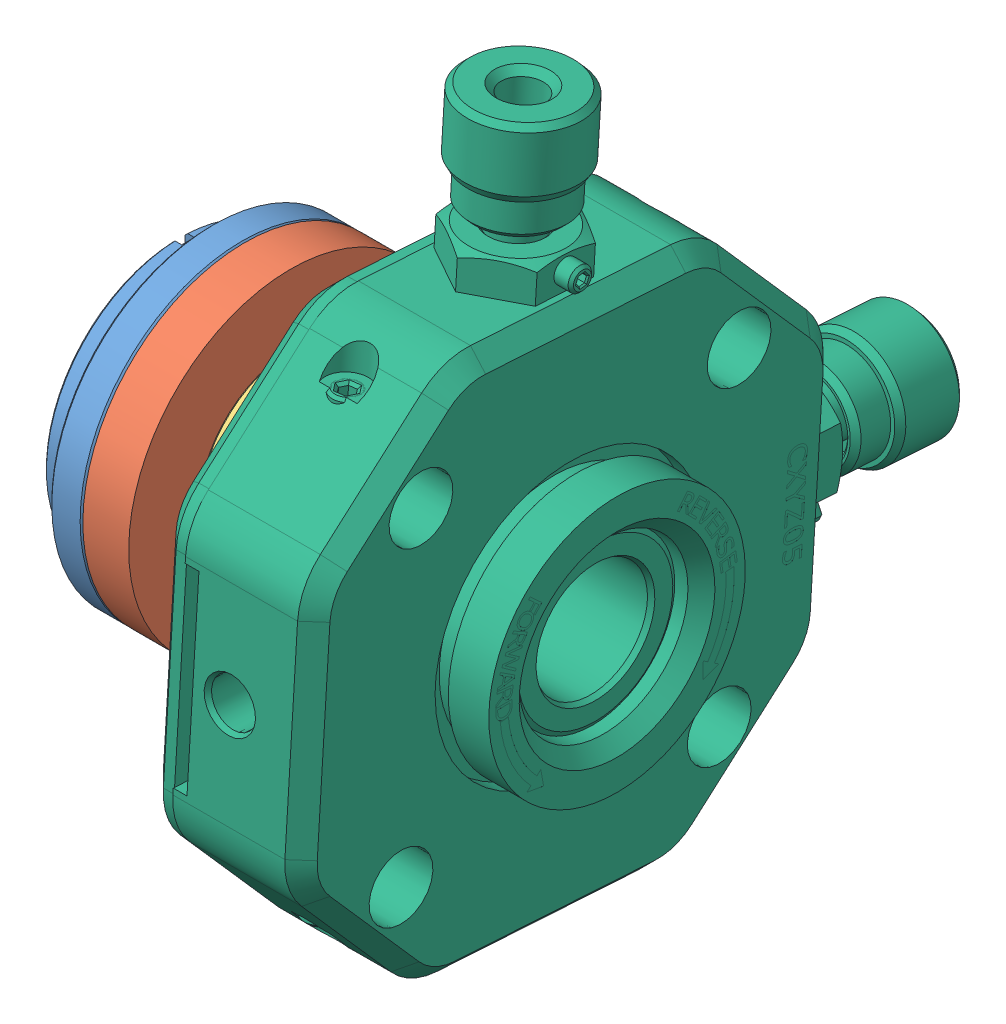
SolidWorks assembly Small Calibration Assembly S05, configuration Default. Lengths in mm.
Overall size (41.25 67.52 67.52).
6 component instances, 6 part files, 10 mates.
Components (placement in the parent):
- SM1A39-Solidworks-1: SM1A39-Solidworks [Default] at (11.2351 18.1088 21.9746) size (9.27 30.48 30.48)
- SM1A1-Solidworks-1: SM1A1-Solidworks [Default] at (-17.3021 33.8201 -40.4992) x (0 0.259133 -0.965842) z (1 0 0) size (30.48 30.48 6.35)
- SM05T1-Solidworks-1: SM05T1-Solidworks [Default] at (38.4613 0.1395 24.8085) size (7.11 17.78 17.78)
- S05TM08-Solidworks-1: S05TM08-Solidworks [Default] at (28.1896 18.1088 21.9746) x (0 -0.170091 0.985428) z (-1 0 0) size (13.59 13.59 6.35)
- C390TME-A-Solidworks-1: C390TME-A-Solidworks [Default] at (26.3987 20.1144 21.5339) x (0 0 1) z (-1 0 0) size (8.21 8.21 5.84)
- CXYZ05-Solidworks-1: CXYZ05-Solidworks [Default] at (9.2525 -14.8097 12.2022) x (0 0.063234 0.997999) z (-1 0 0) size (63.63 63.63 22.07)
Mates (geometry in assembly coordinates):
- Concentric1: concentric aligned: cylinder of SM1A39-Solidworks-1 through (11.2351 18.1088 21.9746) axis (-1 0 0) radius 13.1445; cylinder of SM1A1-Solidworks-1 through (16.3786 18.1088 21.9746) axis (-1 0 0) radius 12.8016
- Coincident1: coincident anti-aligned: plane of SM1A39-Solidworks-1 through (12.8226 18.1088 21.9746) normal (1 0 0); plane of SM1A1-Solidworks-1 through (12.8226 -14.4106 13.2498) normal (-1 0 0)
- Concentric2: concentric aligned: cylinder of SM1A1-Solidworks-1 through (17.1406 18.1088 21.9746) axis (-1 0 0) radius 15.24; cylinder of SM05T1-Solidworks-1 through (15.5979 18.1088 21.9746) axis (-1 0 0) radius 8.89
- Coincident2: coincident anti-aligned: plane of SM1A1-Solidworks-1 through (17.1406 -14.4106 13.2498) normal (1 0 0); plane of SM05T1-Solidworks-1 through (17.1406 26.9988 21.9746) normal (-1 0 0)
- Concentric3: concentric anti-aligned: cylinder of SM05T1-Solidworks-1 through (15.5979 18.1088 21.9746) axis (-1 0 0) radius 6.7945; cylinder of S05TM08-Solidworks-1 through (21.8396 18.1088 21.9746) axis (1 0 0) radius 6.7945
- Coincident3: coincident aligned: plane of SM05T1-Solidworks-1 through (24.2526 24.9033 21.9746) normal (1 0 0); plane of S05TM08-Solidworks-1 through (24.2526 18.1088 21.9746) normal (1 0 0)
- Concentric4: concentric anti-aligned: cylinder of S05TM08-Solidworks-1 through (21.8396 18.1088 21.9746) axis (1 0 0) radius 6.7945; cylinder of C390TME-A-Solidworks-1 through (22.3476 18.1088 21.9746) axis (-1 0 0) radius 4.1072
- Coincident4: coincident aligned: plane of S05TM08-Solidworks-1 through (28.1896 18.1088 21.9746) normal (1 0 0); plane of C390TME-A-Solidworks-1 through (28.1896 14.0016 21.9746) normal (1 0 0)
- Concentric5: concentric: cylinder of S05TM08-Solidworks-1 through (21.8396 18.1088 21.9746) axis (1 0 0) radius 6.7945; cylinder of CXYZ05-Solidworks-1 through (43.7832 18.1088 21.9746) axis (1 0 0) radius 6.7945
- Coincident5: coincident aligned: plane of S05TM08-Solidworks-1 through (25.7766 18.1088 21.9746) normal (-1 0 0); plane of CXYZ05-Solidworks-1 through (25.7766 18.5384 28.7555) normal (-1 0 0)
